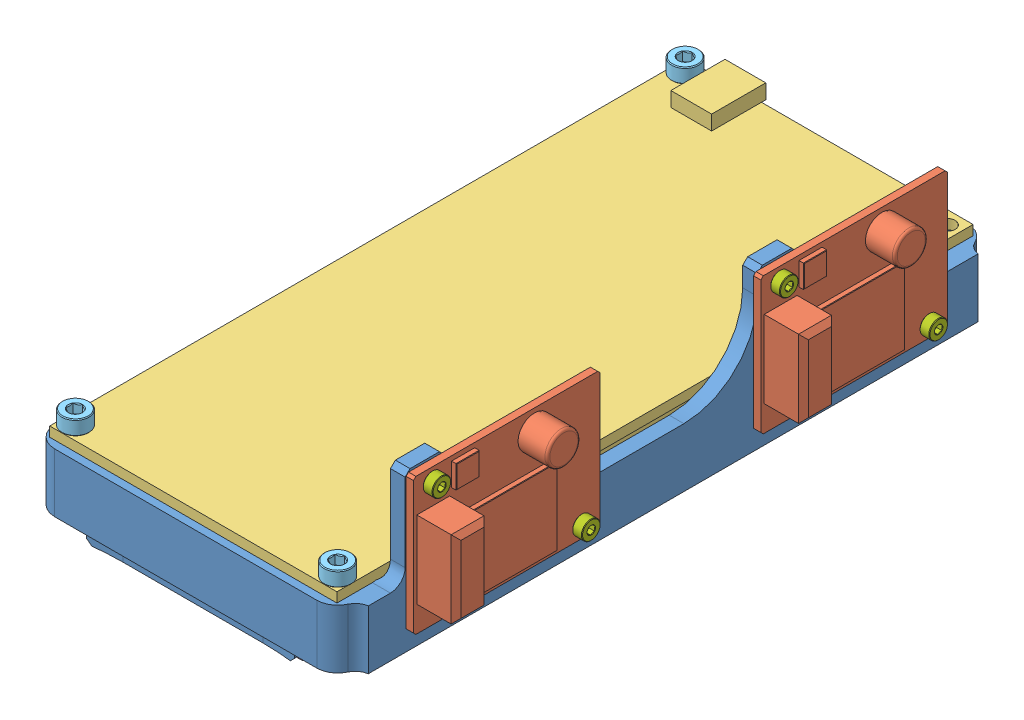
SolidWorks assembly Electronics_Assembly, configuration Default. Lengths in mm.
Overall size (73.5 39.5 132.9).
16 component instances, 7 part files, 39 mates.
Components (placement in the parent):
- 3DPrinted_Electronics_Support-1: 3DPrinted_Electronics_Support [Default] at origin size (64 34.5 132.9)
- Pololu_Motor_Carrier_VNH5019-1: Pololu_Motor_Carrier_VNH5019 [Default] at (33 15.57 35.44) x (0 0 -1) z (1 0 0) size (38.1 27.94 9.5)
- TI_Microcontroller_LAUNCHXL-F28379D-1: TI_Microcontroller_LAUNCHXL-F28379D [Default] at (0 10 0) x (1 0 0) z (0 1 0) size (58.6 130.68 14)
- Pololu_Motor_Carrier_VNH5019-2: Pololu_Motor_Carrier_VNH5019 [Default] at (33 15.57 -35.44) x (0 0 -1) z (1 0 0) size (38.1 27.94 9.5)
- 2802-0004-0008-1: 2802-0004-0008 [Default] at (-16 0.7 57.55) x (-0.994497 0 0.10477) z (0 1 0) size (7.6 7.6 10.21)
- 2802-0004-0008-2: 2802-0004-0008 [Default] at (16 0.7 57.55) x (0.618129 0 -0.786077) z (0 1 0) size (7.6 7.6 10.21)
- 91290A119_BLACK-OXIDE CLASS 12.9 SOCKET HEAD CAP SCREW-1: 91290A119_BLACK-OXIDE CLASS 12.9 SOCKET HEAD CAP SCREW [91290A119] at (-26.75 -2 62.2) x (1 0 0) z (0 -1 0) size (5.5 5.5 17.24)
- 90591A121_ZINC-PLATED STEEL HEX NUT-1: 90591A121_ZINC-PLATED STEEL HEX NUT [90591A121] at (-26.75 0.8 -62.2) x (0.866025 0 0.5) z (-0.5 0 0.866025) size (5.5 2.79 6.35)
- 91290A012_BLACK-OXIDE CLASS 12.9 SOCKET HEAD CAP SCREW-2: 91290A012_BLACK-OXIDE CLASS 12.9 SOCKET HEAD CAP SCREW [91290A012] at (29.5 27 -20.2) x (0 0.924225 0.381849) z (-1 0 0) size (3.8 3.8 7.09)
- 91290A012_BLACK-OXIDE CLASS 12.9 SOCKET HEAD CAP SCREW-3: 91290A012_BLACK-OXIDE CLASS 12.9 SOCKET HEAD CAP SCREW [91290A012] at (29.5 4.14 -50.68) x (0 0.924225 0.381849) z (-1 0 0) size (3.8 3.8 7.09)
- 91290A012_BLACK-OXIDE CLASS 12.9 SOCKET HEAD CAP SCREW-4: 91290A012_BLACK-OXIDE CLASS 12.9 SOCKET HEAD CAP SCREW [91290A012] at (29.5 27 50.68) x (0 0.924225 0.381849) z (-1 0 0) size (3.8 3.8 7.09)
- 91290A012_BLACK-OXIDE CLASS 12.9 SOCKET HEAD CAP SCREW-5: 91290A012_BLACK-OXIDE CLASS 12.9 SOCKET HEAD CAP SCREW [91290A012] at (29.5 4.14 20.2) x (0 0.924225 0.381849) z (-1 0 0) size (3.8 3.8 7.09)
- 91290A119_BLACK-OXIDE CLASS 12.9 SOCKET HEAD CAP SCREW-2: 91290A119_BLACK-OXIDE CLASS 12.9 SOCKET HEAD CAP SCREW [91290A119] at (26.75 -2 62.2) x (1 0 0) z (0 -1 0) size (5.5 5.5 17.24)
- 91290A119_BLACK-OXIDE CLASS 12.9 SOCKET HEAD CAP SCREW-3: 91290A119_BLACK-OXIDE CLASS 12.9 SOCKET HEAD CAP SCREW [91290A119] at (-26.75 -2 -62.2) x (1 0 0) z (0 -1 0) size (5.5 5.5 17.24)
- 90591A121_ZINC-PLATED STEEL HEX NUT-2: 90591A121_ZINC-PLATED STEEL HEX NUT [90591A121] at (26.75 0.8 62.2) x (0.866025 0 0.5) z (-0.5 0 0.866025) size (5.5 2.79 6.35)
- 90591A121_ZINC-PLATED STEEL HEX NUT-3: 90591A121_ZINC-PLATED STEEL HEX NUT [90591A121] at (-26.75 0.8 62.2) x (0.866025 0 -0.5) z (0.5 0 0.866025) size (5.5 2.79 6.35)
Mates (geometry in assembly coordinates):
- Coincident1: coincident aligned: plane of 3DPrinted_Electronics_Support-1 through (0 0 0) normal (1 0 0)
- Coincident2: coincident aligned: plane of 3DPrinted_Electronics_Support-1 through (0 0 0) normal (0 0 1)
- Coincident3: coincident aligned: plane of 3DPrinted_Electronics_Support-1 through (0 0 0) normal (0 1 0)
- Coincident4: coincident anti-aligned: plane of 3DPrinted_Electronics_Support-1 through (26.75 10 62.2) normal (0 1 0); plane of TI_Microcontroller_LAUNCHXL-F28379D-1 through (0 10 0) normal (0 -1 0)
- Concentric1: concentric aligned: cylinder of 3DPrinted_Electronics_Support-1 through (-26.75 10 -62.2) axis (0 -1 0) radius 1.25; cylinder of TI_Microcontroller_LAUNCHXL-F28379D-1 through (-26.75 12 -62.2) axis (0 -1 0) radius 1.6
- Concentric2: concentric aligned: cylinder of 3DPrinted_Electronics_Support-1 through (26.75 10 62.2) axis (0 -1 0) radius 1.25; cylinder of TI_Microcontroller_LAUNCHXL-F28379D-1 through (26.75 12 62.2) axis (0 -1 0) radius 1.6
- Coincident5: coincident anti-aligned: plane of 3DPrinted_Electronics_Support-1 through (33 0 0) normal (1 0 0); plane of Pololu_Motor_Carrier_VNH5019-2 through (33 15.57 -35.44) normal (-1 0 0)
- Concentric3: concentric anti-aligned: cylinder of 3DPrinted_Electronics_Support-1 through (28 4.14 -50.68) axis (1 0 0) radius 1.1; cylinder of Pololu_Motor_Carrier_VNH5019-2 through (34.5 4.14 -50.68) axis (-1 0 0) radius 1
- Concentric4: concentric anti-aligned: cylinder of 3DPrinted_Electronics_Support-1 through (28 27 -20.2) axis (1 0 0) radius 1.1; cylinder of Pololu_Motor_Carrier_VNH5019-2 through (34.5 27 -20.2) axis (-1 0 0) radius 1
- Coincident6: coincident anti-aligned: plane of 3DPrinted_Electronics_Support-1 through (33 0 0) normal (1 0 0); plane of Pololu_Motor_Carrier_VNH5019-1 through (33 15.57 35.44) normal (-1 0 0)
- Concentric5: concentric anti-aligned: cylinder of 3DPrinted_Electronics_Support-1 through (28 4.14 20.2) axis (1 0 0) radius 1.1; cylinder of Pololu_Motor_Carrier_VNH5019-1 through (34.5 4.14 20.2) axis (-1 0 0) radius 1
- Concentric6: concentric anti-aligned: cylinder of 3DPrinted_Electronics_Support-1 through (28 27 50.68) axis (1 0 0) radius 1.1; cylinder of Pololu_Motor_Carrier_VNH5019-1 through (34.5 27 50.68) axis (-1 0 0) radius 1
- Coincident7: coincident aligned: plane of 2802-0004-0008-1 through (-16.3981 -1.5 53.7709) normal (0 -1 0); plane of 2802-0004-0008-2 through (18.9871 -1.5 59.8989) normal (0 -1 0)
- Coincident10: coincident anti-aligned: plane of 3DPrinted_Electronics_Support-1 through (-21.25 -1.5 65) normal (0 1 0); plane of 2802-0004-0008-1 through (-16.3981 -1.5 53.7709) normal (0 -1 0)
- Concentric7: concentric aligned: cylinder of 3DPrinted_Electronics_Support-1 through (-16 -15.8137 57.55) axis (0 1 0) radius 4; circle of 2802-0004-0008-1
- Concentric8: concentric aligned: cylinder of 3DPrinted_Electronics_Support-1 through (16 -15.8137 57.55) axis (0 1 0) radius 4; circle of 2802-0004-0008-2
- Concentric9: concentric aligned: cylinder of Pololu_Motor_Carrier_VNH5019-2 through (34.5 27 -20.2) axis (-1 0 0) radius 1; cylinder of 91290A012_BLACK-OXIDE CLASS 12.9 SOCKET HEAD CAP SCREW-2 through (36.5 27 -20.2) axis (-1 0 0) radius 1.9
- Coincident11: coincident anti-aligned: plane of Pololu_Motor_Carrier_VNH5019-2 through (34.5 15.57 -35.44) normal (1 0 0); plane of 91290A012_BLACK-OXIDE CLASS 12.9 SOCKET HEAD CAP SCREW-2 through (34.5 27 -20.2) normal (-1 0 0)
- Coincident12: coincident aligned: plane of 91290A012_BLACK-OXIDE CLASS 12.9 SOCKET HEAD CAP SCREW-4 through (34.5 27 50.68) normal (-1 0 0); plane of 91290A012_BLACK-OXIDE CLASS 12.9 SOCKET HEAD CAP SCREW-5 through (34.5 4.14 20.2) normal (-1 0 0)
- Coincident13: coincident aligned: plane of 91290A012_BLACK-OXIDE CLASS 12.9 SOCKET HEAD CAP SCREW-3 through (34.5 4.14 -50.68) normal (-1 0 0); plane of 91290A012_BLACK-OXIDE CLASS 12.9 SOCKET HEAD CAP SCREW-4 through (34.5 27 50.68) normal (-1 0 0)
- Coincident14: coincident anti-aligned: plane of Pololu_Motor_Carrier_VNH5019-2 through (34.5 15.57 -35.44) normal (1 0 0); plane of 91290A012_BLACK-OXIDE CLASS 12.9 SOCKET HEAD CAP SCREW-3 through (34.5 4.14 -50.68) normal (-1 0 0)
- Concentric10: concentric aligned: cylinder of Pololu_Motor_Carrier_VNH5019-2 through (34.5 4.14 -50.68) axis (-1 0 0) radius 1; cylinder of 91290A012_BLACK-OXIDE CLASS 12.9 SOCKET HEAD CAP SCREW-3 through (36.5 4.14 -50.68) axis (-1 0 0) radius 1.9
- Concentric11: concentric anti-aligned: circle of Pololu_Motor_Carrier_VNH5019-1; cylinder of 91290A012_BLACK-OXIDE CLASS 12.9 SOCKET HEAD CAP SCREW-5 through (36.5 4.14 20.2) axis (-1 0 0) radius 1.9
- Concentric12: concentric aligned: cylinder of Pololu_Motor_Carrier_VNH5019-1 through (34.5 27 50.68) axis (-1 0 0) radius 1; cylinder of 91290A012_BLACK-OXIDE CLASS 12.9 SOCKET HEAD CAP SCREW-4 through (36.5 27 50.68) axis (-1 0 0) radius 1.9
- Coincident16: coincident aligned: plane of 91290A119_BLACK-OXIDE CLASS 12.9 SOCKET HEAD CAP SCREW-1 through (-26.75 12 62.2) normal (0 -1 0); plane of 91290A119_BLACK-OXIDE CLASS 12.9 SOCKET HEAD CAP SCREW-3 through (-26.75 12 -62.2) normal (0 -1 0)
- Coincident17: coincident aligned: plane of 91290A119_BLACK-OXIDE CLASS 12.9 SOCKET HEAD CAP SCREW-2 through (26.75 12 62.2) normal (0 -1 0); plane of 91290A119_BLACK-OXIDE CLASS 12.9 SOCKET HEAD CAP SCREW-3 through (-26.75 12 -62.2) normal (0 -1 0)
- Coincident18: coincident anti-aligned: plane of TI_Microcontroller_LAUNCHXL-F28379D-1 through (0 12 0) normal (0 1 0); plane of 91290A119_BLACK-OXIDE CLASS 12.9 SOCKET HEAD CAP SCREW-3 through (-26.75 12 -62.2) normal (0 -1 0)
- Concentric13: concentric aligned: cylinder of TI_Microcontroller_LAUNCHXL-F28379D-1 through (-26.75 12 -62.2) axis (0 -1 0) radius 1.6; cylinder of 91290A119_BLACK-OXIDE CLASS 12.9 SOCKET HEAD CAP SCREW-3 through (-26.75 15 -62.2) axis (0 -1 0) radius 2.75
- Concentric14: concentric aligned: cylinder of TI_Microcontroller_LAUNCHXL-F28379D-1 through (-26.75 12 62.2) axis (0 -1 0) radius 1.6; cylinder of 91290A119_BLACK-OXIDE CLASS 12.9 SOCKET HEAD CAP SCREW-1 through (-26.75 15 62.2) axis (0 -1 0) radius 2.75
- Concentric15: concentric aligned: cylinder of TI_Microcontroller_LAUNCHXL-F28379D-1 through (26.75 12 62.2) axis (0 -1 0) radius 1.6; cylinder of 91290A119_BLACK-OXIDE CLASS 12.9 SOCKET HEAD CAP SCREW-2 through (26.75 15 62.2) axis (0 -1 0) radius 2.75
- Coincident19: coincident aligned: plane of 90591A121_ZINC-PLATED STEEL HEX NUT-1 through (-28.3377 2 -64.95) normal (0 1 0); plane of 90591A121_ZINC-PLATED STEEL HEX NUT-3 through (-29.8586 0.454 61.2335) normal (0 1 0)
- Coincident20: coincident aligned: plane of 90591A121_ZINC-PLATED STEEL HEX NUT-2 through (25.1623 2 59.45) normal (0 1 0); plane of 90591A121_ZINC-PLATED STEEL HEX NUT-3 through (-29.8586 0.454 61.2335) normal (0 1 0)
- Concentric16: concentric anti-aligned: circle of 90591A121_ZINC-PLATED STEEL HEX NUT-1; cylinder of 91290A119_BLACK-OXIDE CLASS 12.9 SOCKET HEAD CAP SCREW-3 through (-26.75 15 -62.2) axis (0 -1 0) radius 2.75
- Concentric17: concentric anti-aligned: cylinder of 91290A119_BLACK-OXIDE CLASS 12.9 SOCKET HEAD CAP SCREW-1 through (-26.75 15 62.2) axis (0 -1 0) radius 2.75; circle of 90591A121_ZINC-PLATED STEEL HEX NUT-3
- Concentric18: concentric anti-aligned: cylinder of 91290A119_BLACK-OXIDE CLASS 12.9 SOCKET HEAD CAP SCREW-2 through (26.75 15 62.2) axis (0 -1 0) radius 2.75; circle of 90591A121_ZINC-PLATED STEEL HEX NUT-2
- Coincident22: coincident anti-aligned: plane of 3DPrinted_Electronics_Support-1 through (0 2 0) normal (0 -1 0); plane of 90591A121_ZINC-PLATED STEEL HEX NUT-1 through (-28.3377 2 -64.95) normal (0 1 0)
- Parallel1: parallel anti-aligned: plane of 3DPrinted_Electronics_Support-1 through (-25.0179 2 -59.2) normal (0 0 -1); plane of 90591A121_ZINC-PLATED STEEL HEX NUT-1 through (-28.3377 2 -59.45) normal (0 0 1)
- Parallel2: parallel anti-aligned: plane of 3DPrinted_Electronics_Support-1 through (28.4821 2 65.2) normal (0 0 -1); plane of 90591A121_ZINC-PLATED STEEL HEX NUT-2 through (25.1623 2 64.95) normal (0 0 1)
- Parallel3: parallel aligned: plane of 3DPrinted_Electronics_Support-1 through (-30.2141 2 62.2) normal (0.866025 0 0.5); plane of 90591A121_ZINC-PLATED STEEL HEX NUT-3 through (-25.1623 2 64.95) normal (0.866025 0 0.5)
